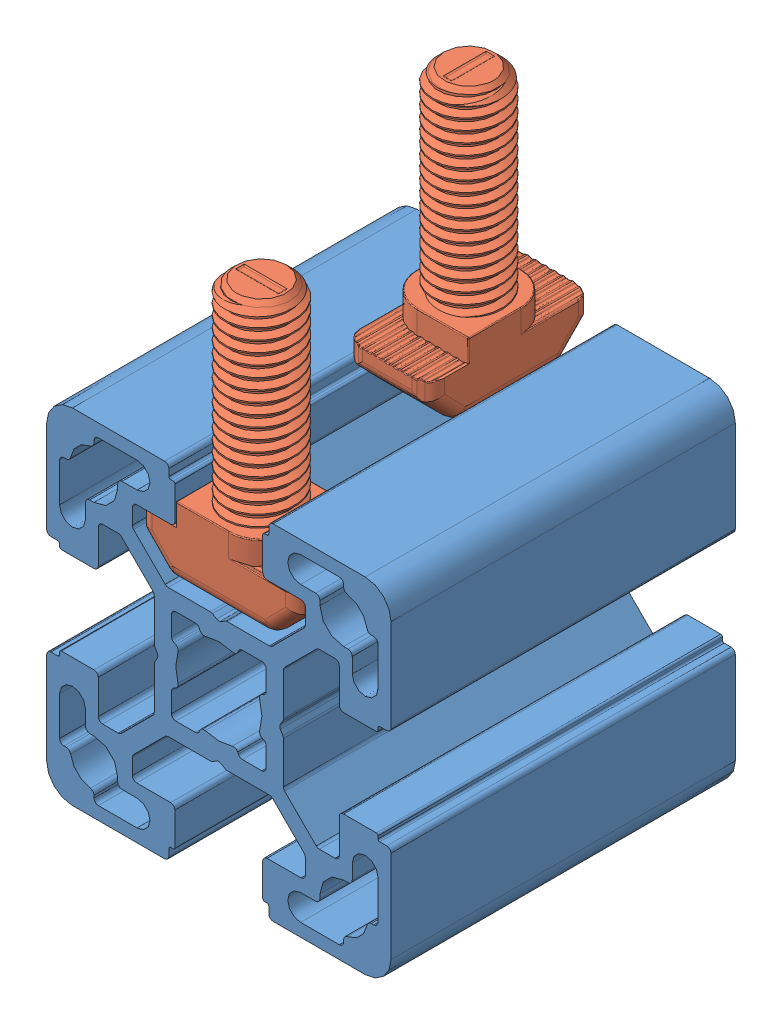
SolidWorks assembly Сборка Т-Болт паз10, configuration По умолчанию. Lengths in mm.
Overall size (40 68.44 40.01).
3 component instances, 2 part files, 5 mates.
Components (placement in the parent):
- 40х40-1: 40х40 [По умолчанию] at origin size (40 40 40)
- Т-Болт 10паз М8х25 с шариком-1: Т-Болт 10паз М8х25 с шариком [По умолчанию] at (0 8.4 35.05) size (19 33.12 9.91)
- Т-Болт 10паз М8х25 с шариком-2: Т-Болт 10паз М8х25 с шариком [По умолчанию] at (0.05 17.8115 11.0058) x (0 0 -1) z (1 0 0) size (19 33.12 9.91)
Mates (geometry in assembly coordinates):
- Совпадение1: coincident aligned: plane of Т-Гайка 10 паз-1 through (5 14 30.1) normal (1 0 0); plane of Т-Гайка 10 паз-2 through (5 17.8115 11.0058) normal (1 0 0)
- Параллельность1: parallel anti-aligned: plane of Т-Гайка 10 паз-1 through (-5 16.6 30.1) normal (0 1 0); plane of Т-Гайка 10 паз-2 through (-4.9 17.8115 5.0058) normal (0 -1 0)
- Совпадение3: coincident aligned: plane of 40х40-1 through (0 0 40) normal (0 0 1); plane of Т-Гайка 10 паз-1 through (0 8.4 40) normal (0 0 1)
- Совпадение4: coincident anti-aligned: plane of 40х40-1 through (0 14 40) normal (0 -1 0); plane of Т-Гайка 10 паз-1 through (-9.5 14 30.1) normal (0 1 0)
- Расстояние1: distance = 0.1 mm anti-aligned: plane of 40х40-1 through (-5.1 0 40) normal (1 0 0); plane of Т-Гайка 10 паз-1 through (-5 14 30.1) normal (-1 0 0)
